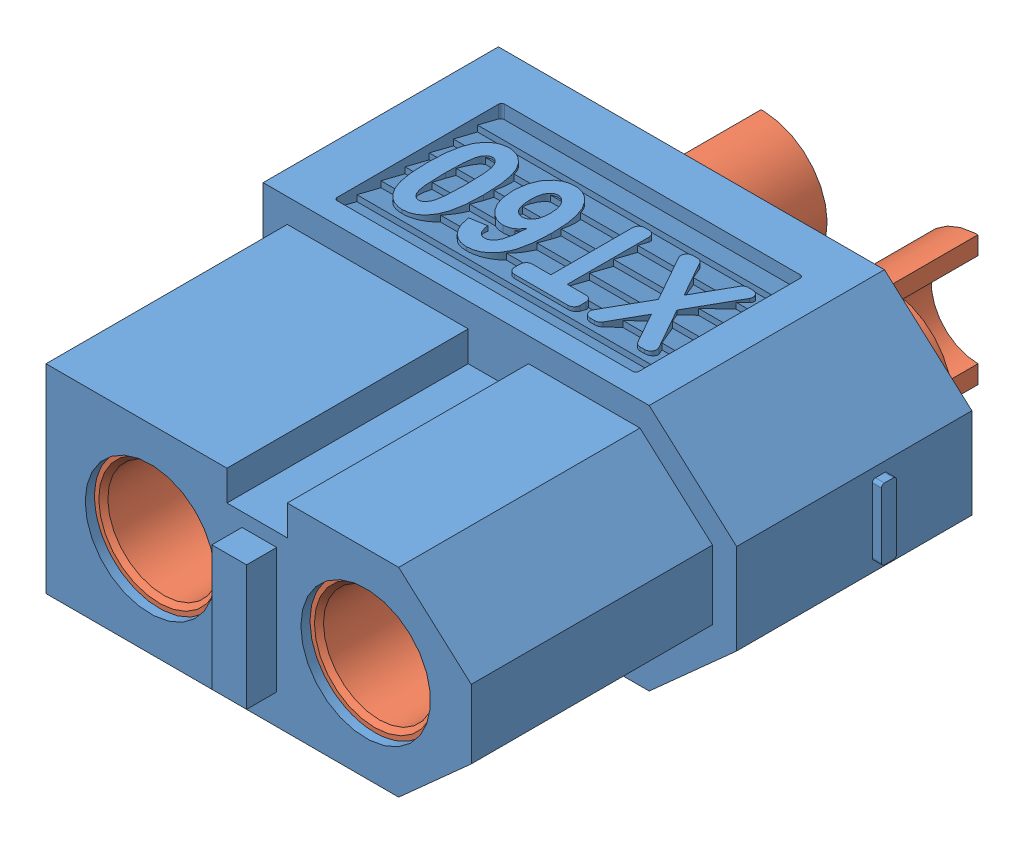
SolidWorks assembly XT-60_Femea, configuration Valor predeterminado. Lengths in mm.
Overall size (16.3 8.2 28.3).
3 component instances, 2 part files, 4 mates.
Components (placement in the parent):
- XT-60_Femea-1: XT-60_Femea [Valor predeterminado] at (-45.4071 14.4296 -8.6) size (16.3 8.2 16.8)
- PinoXT-60_Femea-1: PinoXT-60_Femea [Valor predeterminado] at (-41.1571 18.5296 -13.1) x (0.019097 -0.999818 0) z (-0.999818 -0.019097 0) size (4.3 27 4.3)
- PinoXT-60_Femea-2: PinoXT-60_Femea [Valor predeterminado] at (-34.0071 18.5296 -13.1) x (-0.00106 0.999999 0) z (0.999999 0.00106 0) size (4.3 27 4.3)
Mates (geometry in assembly coordinates):
- Concêntrico1: concentric aligned: cylinder of XT-60_Femea-1 through (-41.1571 18.5296 7.2) axis (0 0 -1) radius 2.15; cylinder of PinoXT-60_Femea-1 through (-41.1571 18.5296 -9.1) axis (0 0 -1) radius 2.15
- Concêntrico2: concentric aligned: cylinder of XT-60_Femea-1 through (-34.0071 18.5296 7.2) axis (0 0 -1) radius 2.15; cylinder of PinoXT-60_Femea-2 through (-34.0071 18.5296 -9.1) axis (0 0 -1) radius 2.15
- Distância1: distance = 0.3 mm aligned: plane of PinoXT-60_Femea-1 through (-41.116 16.38 6.9) normal (0 0 1); plane of XT-60_Femea-1 through (-45.4071 14.4296 7.2) normal (0 0 1)
- Distância2: distance = 0.3 mm aligned: plane of PinoXT-60_Femea-2 through (-34.0094 20.6796 6.9) normal (0 0 1); plane of XT-60_Femea-1 through (-45.4071 14.4296 7.2) normal (0 0 1)
